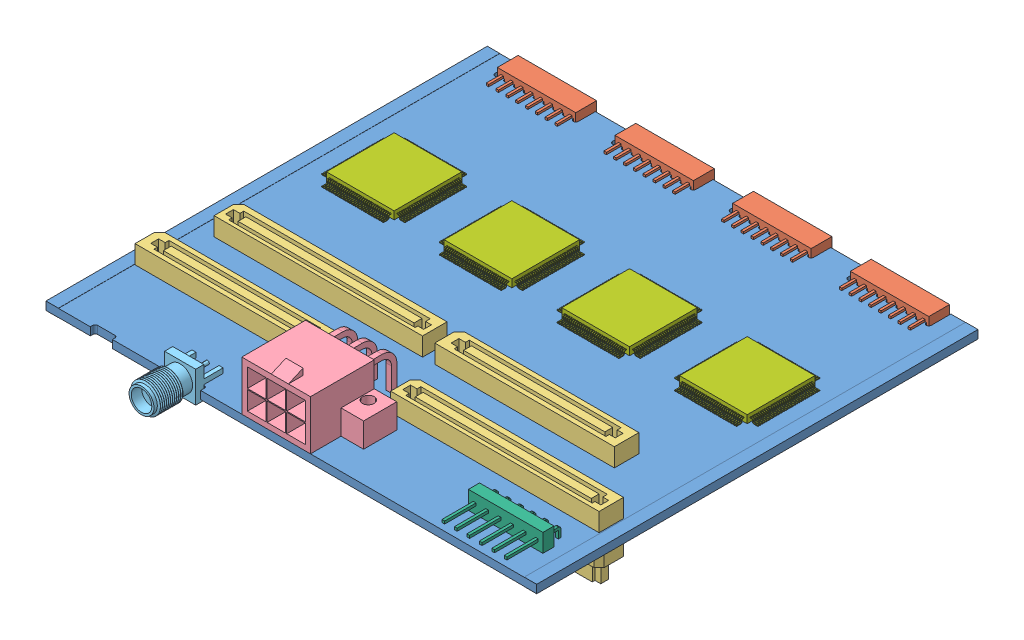
SolidWorks assembly carrier02.revB, configuration Default. Lengths in mm.
Overall size (100.07 21.59 98.54).
13 component instances, 7 part files, 14 mates.
Components (placement in the parent):
- carrier02.revB.PCB-1: carrier02.revB.PCB [Default] at (0 0 11) size (100.07 1.69 90)
- connector.2mm.16-pin.female-1: connector.2mm.16-pin.female [Default] at (6 -1.33 -75) x (1 0 0) z (0 1 0) size (16 7.25 4.25)
- connector.2mm.16-pin.female-5: connector.2mm.16-pin.female [Default] at (30 -1.33 -75) x (1 0 0) z (0 1 0) size (16 7.25 4.25)
- connector.2mm.16-pin.female-6: connector.2mm.16-pin.female [Default] at (54 -1.33 -75) x (1 0 0) z (0 1 0) size (16 7.25 4.25)
- connector.2mm.16-pin.female-7: connector.2mm.16-pin.female [Default] at (78 -1.33 -75) x (1 0 0) z (0 1 0) size (16 7.25 4.25)
- board-interconnects.100-and-120-pin.bottom-SV4.top-SV.carrier02-1: board-interconnects.100-and-120-pin.bottom-SV4.top-SV.carrier02 [Default] at (0 1.6154 0) size (94.62 13.94 18)
- molex-mini-fit-jr-6-pin-right-angle.simplified-1: molex-mini-fit-jr-6-pin-right-angle.simplified [Default] at (39.9002 1.6154 11) size (23.2 15 20.05)
- SMA.PC-edge-mount.short-1: SMA.PC-edge-mount.short [Default] at (30.9125 -1.07 9.75) x (-1 0 0) z (0 0 -1) size (6.35 6.35 13.46)
- 6-pin-0.1-inch-right-angle-1: 6-pin-0.1-inch-right-angle [Default] at (79.978 1.5222 4.87) size (15.2 6.2 11.02)
- TQFP-128-2: TQFP-128 [Default] at (7.3144 1.6154 -38.85) size (17 1.6 17)
- TQFP-128-3: TQFP-128 [Default] at (31.3144 1.6154 -38.85) size (17 1.6 17)
- TQFP-128-4: TQFP-128 [Default] at (55.3144 1.6154 -38.85) size (17 1.6 17)
- TQFP-128-5: TQFP-128 [Default] at (79.3144 1.6154 -38.85) size (17 1.6 17)
Mates (geometry in assembly coordinates):
- Coincident2: coincident anti-aligned: plane of carrier02.revB.PCB-1 through (31 1.6154 10.2) normal (0 1 0); plane of board-interconnects.100-and-120-pin.bottom-SV4.top-SV.carrier02-1 through (51.75 1.6154 -17.5) normal (0 -1 0)
- Coincident3: coincident aligned: plane of carrier02.revB.PCB-1 through (31.5 1.6154 11) normal (0 0 1); plane of molex-mini-fit-jr-6-pin-right-angle.simplified-1 through (40.7144 11.7154 11) normal (0 0 1)
- Coincident4: coincident anti-aligned: plane of carrier02.revB.PCB-1 through (31 1.6154 10.2) normal (0 1 0); plane of molex-mini-fit-jr-6-pin-right-angle.simplified-1 through (40.7144 1.6154 11) normal (0 -1 0)
- Distance1: distance = 39.625 mm aligned: plane of molex-mini-fit-jr-6-pin-right-angle.simplified-1 through (39.5894 11.7154 11) normal (-1 0 0); plane of carrier02.revB.PCB-1 through (-0.0356 0 11) normal (-1 0 0)
- Coincident5: coincident anti-aligned: plane of carrier02.revB.PCB-1 through (31 1.6154 9.75) normal (0 0 1); plane of SMA.PC-edge-mount.short-1 through (30.9125 5.28 9.75) normal (0 0 -1)
- Coincident6: coincident anti-aligned: plane of carrier02.revB.PCB-1 through (6 0 -75) normal (0 -1 0); plane of SMA.PC-edge-mount.short-1 through (24.5625 0 5.83) normal (0 1 0)
- Distance2: distance = 0.0625 mm: line of carrier02.revB.PCB-1 through (24.5 1.6154 9.75) axis (0 -1 0); line of SMA.PC-edge-mount.short-1 through (24.5625 5.28 9.75) axis (0 -1 0)
- Distance3: distance = 43 mm: plane of carrier02.revB.PCB-1 through (-0.0356 1.651 -79) normal (-1 0 0); line of molex-mini-fit-jr-6-pin-right-angle.simplified-1 through (42.9644 -6.5503 -3) axis (0 1 0)
- Distance4: distance = 14 mm: line of molex-mini-fit-jr-6-pin-right-angle.simplified-1 through (42.9644 -6.5503 -3) axis (0 1 0); plane of carrier02.revB.PCB-1 through (100 1.6154 11) normal (0 0 1)
- Distance5: distance = 10.5 mm: line of 6-pin-0.1-inch-right-angle-1 through (81.2444 6.2929 0.5) axis (0 -1 0); plane of carrier02.revB.PCB-1 through (100 1.6154 11) normal (0 0 1)
- Distance6: distance = 81.28 mm: line of 6-pin-0.1-inch-right-angle-1 through (81.2444 6.2929 0.5) axis (0 -1 0); plane of carrier02.revB.PCB-1 through (-0.0356 1.651 -79) normal (-1 0 0)
- Coincident11: coincident anti-aligned: plane of carrier02.revB.PCB-1 through (6 1.6154 -75) normal (0 1 0); plane of TQFP-128-2 through (7.3144 1.6154 -38.85) normal (0 -1 0)
- Distance7: distance = 14.25 mm: line of TQFP-128-2 through (14.2144 4.2014 -45.75) axis (0 -1 0); plane of carrier02.revB.PCB-1 through (-0.0356 1.651 -79) normal (-1 0 0)
- Distance8: distance = 56.75 mm: line of TQFP-128-2 through (14.2144 4.2014 -45.75) axis (0 -1 0); plane of carrier02.revB.PCB-1 through (24 1.6154 11) normal (0 0 1)
